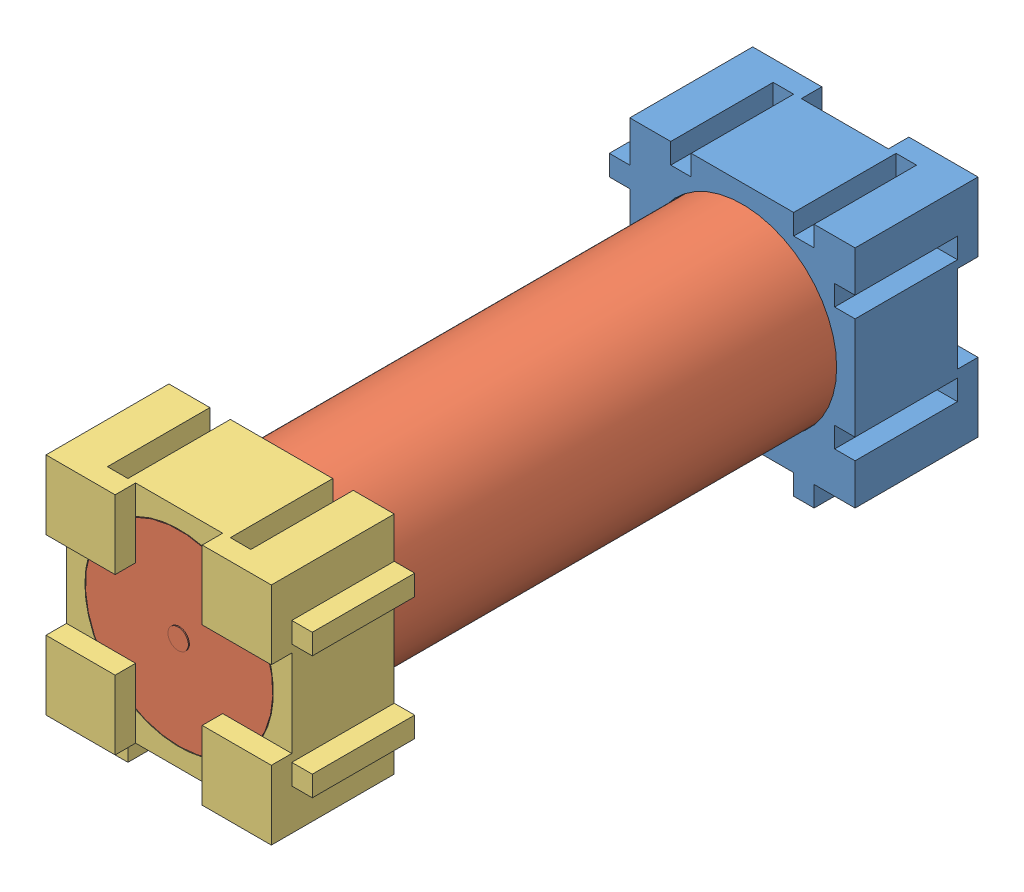
SolidWorks assembly ModuleWithM3EndCap, configuration Default. Lengths in mm.
Overall size (26 24.96 69).
3 component instances, 3 part files, 5 mates.
Components (placement in the parent):
- EndCapWithM3-1: EndCapWithM3 [Default] at (-29.8572 11.8608 5.2524) size (24 24 12)
- HB2-1: HB2 [Default] at (-28.2562 10.1049 70.2524) x (0.923728 0.383049 0) z (0.383049 -0.923728 0) size (18.3 65.2 18.3)
- EndCap-1: EndCap [Default] at (-26.6553 11.8608 70.2524) x (-1 0 0) z (0 0 -1) size (24 24 12)
Mates (geometry in assembly coordinates):
- Concentric1: concentric aligned: circle of EndCapWithM3-1; circle of HB2-1
- Coincident1: coincident anti-aligned: plane of EndCapWithM3-1 through (-29.8572 11.8608 5.2524) normal (0 0 1); plane of HB2-1 through (-28.2562 10.1049 5.2524) normal (0 0 -1)
- Coincident4: coincident anti-aligned: plane of HB2-1 through (-28.2562 10.1049 70.2524) normal (0 0 1); plane of EndCap-1 through (-26.6553 11.8608 70.2524) normal (0 0 -1)
- Concentric3: concentric anti-aligned: circle of HB2-1; circle of EndCap-1
- Parallel2: parallel anti-aligned: line of EndCapWithM3-1 through (-23.2562 21.1049 15.2524) axis (-1 0 0); line of EndCap-1 through (-33.2562 21.1049 60.2524) axis (1 0 0)
